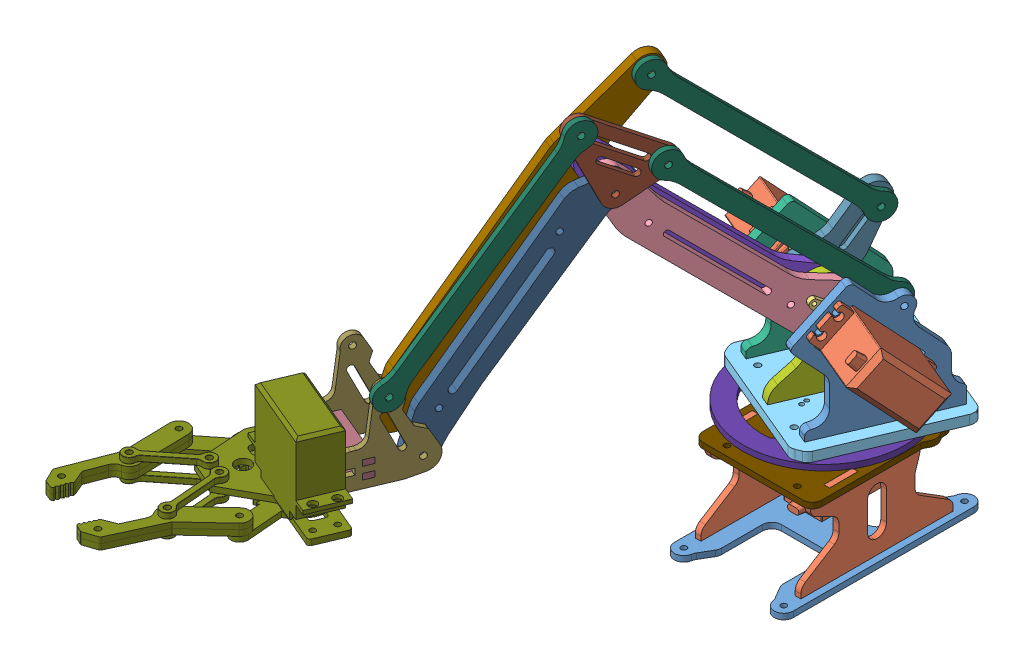
SolidWorks assembly UiRS.1 - Robot Arm 3DOF, configuration Default. Lengths in mm.
Overall size (217.77 238.48 366.27).
29 component instances, 20 part files, 0 mates.
Components (placement in the parent):
- Part1-1: Part1 [Default] at (37.2995 -22.8679 90.5475) x (0.921426 0 0.388553) z (-0.388553 0.000001 0.921426) size (5 71.67 70.43)
- Servo - Tower Pro MG995-1: Servo - Tower Pro MG995 [Default] at (80.3427 17.1321 80.2243) x (0.274748 -0.707107 -0.651546) z (0.274748 0.707106 -0.651548) size (54.65 45.95 20.01)
- [Komp] Star Horn for MG995-1: [Komp] Star Horn for MG995 [Default] at (35.9471 23.3723 68.2756) x (-0.084661 -0.975974 0.200768) z (-0.921426 0 -0.388553) size (31.62 27.96 6)
- Part3-1: Part3 [Default] at (31.34 23.3723 66.3328) x (0.921426 0 0.388553) z (-0.286082 0.676683 0.678422) size (5 30 147.5)
- Part4-1: Part4 [Default] at (24.6804 -22.8679 49.9548) x (0.921426 0 0.388553) z (-0.388553 0.000001 0.921426) size (75.8 5 75)
- Part11-1: Part11 [Default] at (-15.9589 -22.8679 68.0892) x (0.921426 0 0.388553) z (-0.388553 0.000001 0.921426) size (5 71.67 70.43)
- [Komp] Star Horn for MG995-2: [Komp] Star Horn for MG995 [Default] at (5.54 23.3723 55.4533) x (-0.145102 0.927654 0.344098) z (0.921426 0 0.388553) size (31.62 27.96 6)
- Servo - Tower Pro MG995-2: Servo - Tower Pro MG995 [Default] at (-34.0063 17.1321 32.0048) x (0.274748 -0.707107 -0.651546) z (-0.274748 -0.707106 0.651548) size (54.65 45.95 20.01)
- Part22-1: Part22 [Default] at (22.1271 -17.8679 62.444) x (0.921426 0 0.388553) z (-0.388553 0.000001 0.921426) size (5 58.74 47.5)
- Part122-1: Part122 [Default] at (17.52 23.3721 60.5012) x (0.921426 0 0.388553) z (-0.286082 0.676683 0.678422) size (5 27 145)
- Part5-1: Part5 [Default] at (-22.8474 107.9575 143.3613) x (0.921426 0 0.388553) z (-0.239581 -0.787278 0.56815) size (5 23.48 180)
- Part25-1: Part25 [Default] at (0.1869 107.9578 153.0783) x (0.921426 0 0.388553) z (-0.239581 -0.787278 0.56815) size (5 23.43 140)
- Part6-1: Part6 [Default] at (3.8726 107.9578 154.6326) x (0.921426 0 0.388553) z (-0.388553 0.00024 0.921426) size (3 45 47.5)
- Part7-1: Part7 [Default] at (-26.075 9.548 225.6512) x (0.921426 0 0.388553) z (-0.388553 0.00024 0.921426) size (3 46.12 45)
- Part8-1: Part8 [Default] at (-52.352 12.6798 245.5001) x (0.921426 0 0.388553) z (-0.388553 0.00024 0.921426) size (36 3 18)
- Part8-2: Part8 [Default] at (-52.3525 6.4298 245.5015) x (0.921426 0 0.388553) z (-0.388553 0.00024 0.921426) size (36 3 18)
- Part9-1: Part9 [Default] at (10.1472 23.3723 57.3961) x (0.921426 0 0.388553) z (-0.239602 -0.787236 0.5682) size (5 30 62.5)
- Part10-1: Part10 [Default] at (8.3014 97.1552 79.7887) x (0.921426 0 0.388553) z (-0.286077 0.676695 0.678412) size (3 13.5 138.5)
- Part10-2: Part10 [Default] at (32.2892 75.6609 94.9656) x (0.921426 0 0.388553) z (-0.286085 0.676673 0.678431) size (3 13.5 138.5)
- Part10-3: Part10 [Default] at (-14.1622 91.2565 205.1218) x (0.921426 0 0.388553) z (0.239581 0.787278 -0.56815) size (3 13.5 138.5)
- ARM MG995-1: ARM MG995 [Default] at (8.279 -65.6889 299.6168) x (0.921426 0 0.388553) z (-0.388553 0.00024 0.921426) size (89.39 49 109.64)
- Part7-2: Part7 [Default] at (-56.4807 9.5477 212.8257) x (0.921426 0 0.388553) z (-0.388553 0.00024 0.921426) size (3 46.12 45)
- Servo - Tower Pro MG995-3: Servo - Tower Pro MG995 [Default] at (22.1271 -70.9179 53.6191) x (0 -0.000001 -1) z (1 0 0) size (54.65 45.95 20.01)
- [Komp] Star Horn for MG995-3: [Komp] Star Horn for MG995 [Default] at (22.1271 -25.3679 62.4441) x (0.921426 0 0.388553) z (0 1 -0.000001) size (31.62 27.96 6)
- Part1212-1: Part1212 [Default] at (22.1271 -24.3679 62.4441) x (0.921426 0 0.388553) z (-0.388553 0.000001 0.921426) size (85 3 92)
- BaseArmUpper-1: BaseArmUpper [Default] at (22.1271 -38.7679 53.6191) x (0 -0.000001 -1) z (1 0 0) size (75 3 66.5)
- BaseArmBase-1: BaseArmBase [Default] at (22.1271 -81.7679 62.4441) x (0 -0.000001 -1) z (1 0 0) size (105 3 62.5)
- BaseArmSide-1: BaseArmSide [Default] at (48.3771 -83.2679 62.4441) x (1 0 0) z (0 0.000001 1) size (3 46 80)
- BaseArmSide-2: BaseArmSide [Default] at (-4.1229 -83.2679 62.4441) x (1 0 0) z (0 0.000001 1) size (3 46 80)
